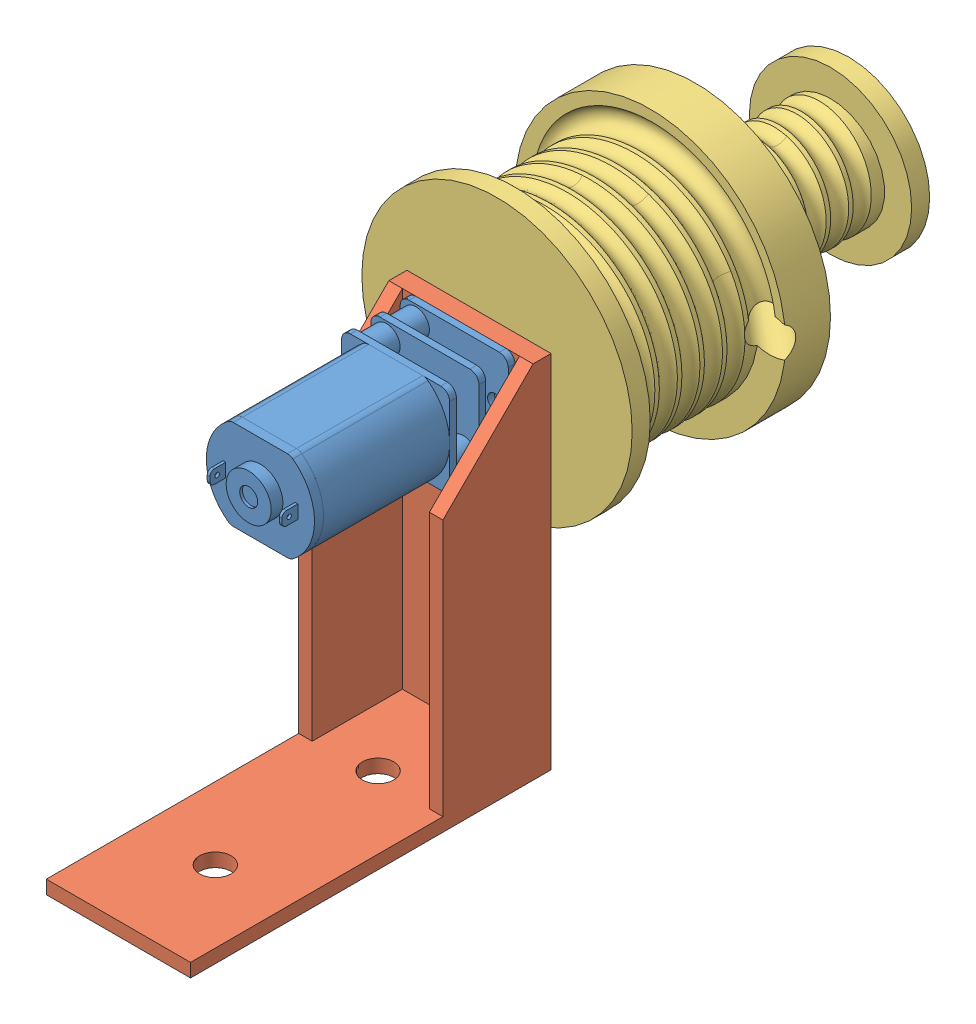
SolidWorks assembly Winch_assembly, configuration Default. Lengths in mm.
Overall size (30 50 81).
3 component instances, 3 part files, 6 mates.
Components (placement in the parent):
- DC Motor-1: DC Motor [Default] at (-1.6009 14.5601 35.8681) size (12 10 34.05)
- Winch_wheel_holder_idea-1: Winch_wheel_holder_idea [Default] at (-9.6009 -20.4399 12.6181) x (1 0 0) z (0 -1 0) size (16 40 40)
- Winch_wheel_idea-1: Winch_wheel_idea [Default] at (-1.6009 14.5601 8.6181) x (0 0 -1) z (-1 0 0) size (39 30 30)
Mates (geometry in assembly coordinates):
- Concentric1: concentric aligned: cylinder of DC Motor-1 through (-1.6009 14.5601 4.5681) axis (0 0 1) radius 1.5; cylinder of Winch_wheel_idea-1 through (-1.6009 14.5601 3.6181) axis (0 0 1) radius 1.5
- Coincident1: coincident anti-aligned: plane of DC Motor-1 through (-1.6009 15.5601 35.8681) normal (0 1 0); plane of Winch_wheel_idea-1 through (-0.4829 15.5601 3.6181) normal (0 -1 0)
- Concentric2: concentric anti-aligned: cylinder of DC Motor-1 through (-1.6009 14.5601 13.8181) axis (0 0 1) radius 2; cylinder of Winch_wheel_holder_idea-1 through (-1.6009 14.5601 14.6181) axis (0 0 -1) radius 2.3
- Coincident2: coincident anti-aligned: plane of DC Motor-1 through (-1.6009 14.5601 14.6181) normal (0 0 -1); plane of Winch_wheel_holder_idea-1 through (-9.6009 -20.4399 14.6181) normal (0 0 1)
- Coincident3: coincident aligned: plane of DC Motor-1 through (-7.6009 19.5601 14.6181) normal (0 1 0); plane of Winch_wheel_holder_idea-1 through (-9.6009 19.5601 14.6181) normal (0 1 0)
- Distance1: distance = 2 mm anti-aligned: plane of Winch_wheel_idea-1 through (-1.6009 14.5601 10.6181) normal (0 0 1); plane of Winch_wheel_holder_idea-1 through (-9.6009 -20.4399 12.6181) normal (0 0 -1)
